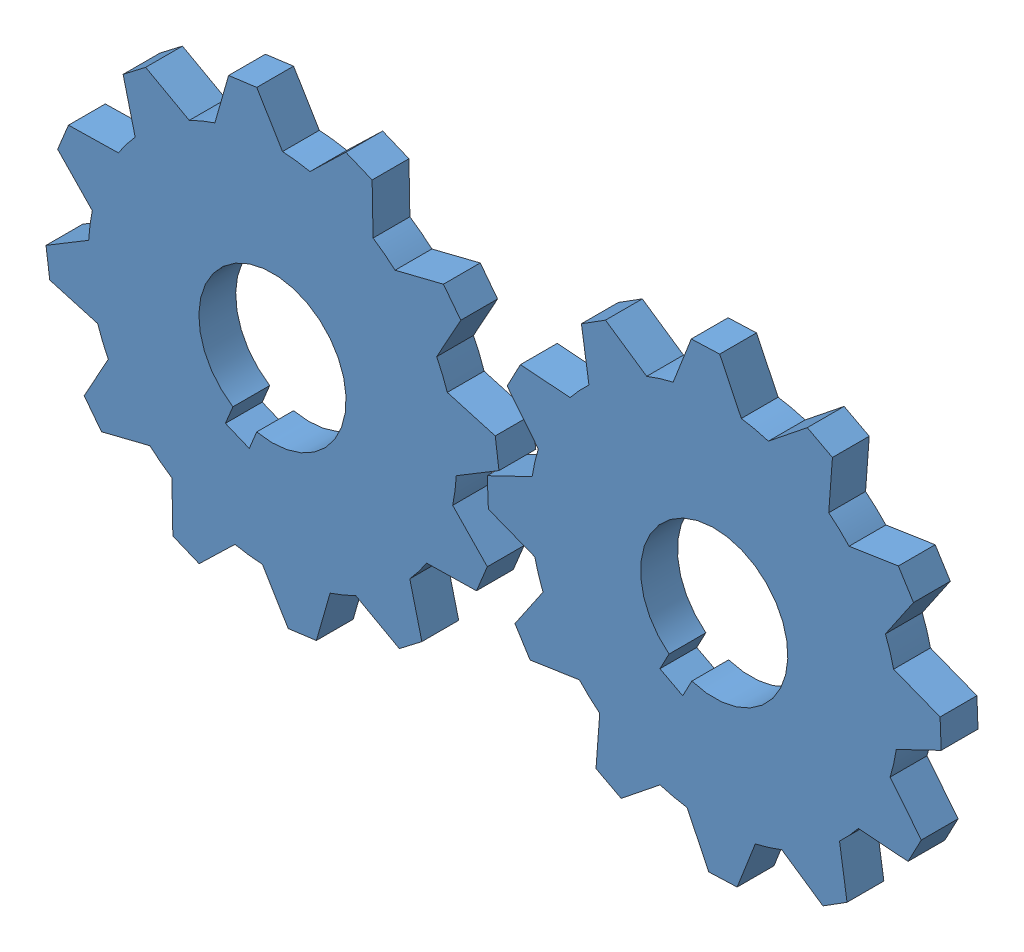
SolidWorks assembly Test_4, configuration Default. Lengths in mm.
Overall size (283.54 166.3 10).
2 component instances, 1 part files, 5 mates.
Components (placement in the parent):
- Gear_1-3: Gear_1 [Default] at (-135.0613 134.9481 -10) x (0.884671 -0.466216 0) z (0 0 1) size (123.1 123.1 10)
- Gear_1-4: Gear_1 [Default] at (-255.0613 134.9481 -10) x (0.924261 -0.38176 0) z (0 0 1) size (123.1 123.1 10)
Mates (geometry in assembly coordinates):
- Coincident1: coincident aligned: plane of Gear_1-4 through (-255.0613 134.9481 0) normal (0 0 1)
- Coincident2: coincident aligned: plane of Gear_1-3 through (-135.0613 134.9481 0) normal (0 0 1)
- Concentric6: concentric anti-aligned: circle of Gear_1-4
- Concentric7: concentric anti-aligned: circle of Gear_1-4
- Concentric10: concentric anti-aligned: circle of Gear_1-3
